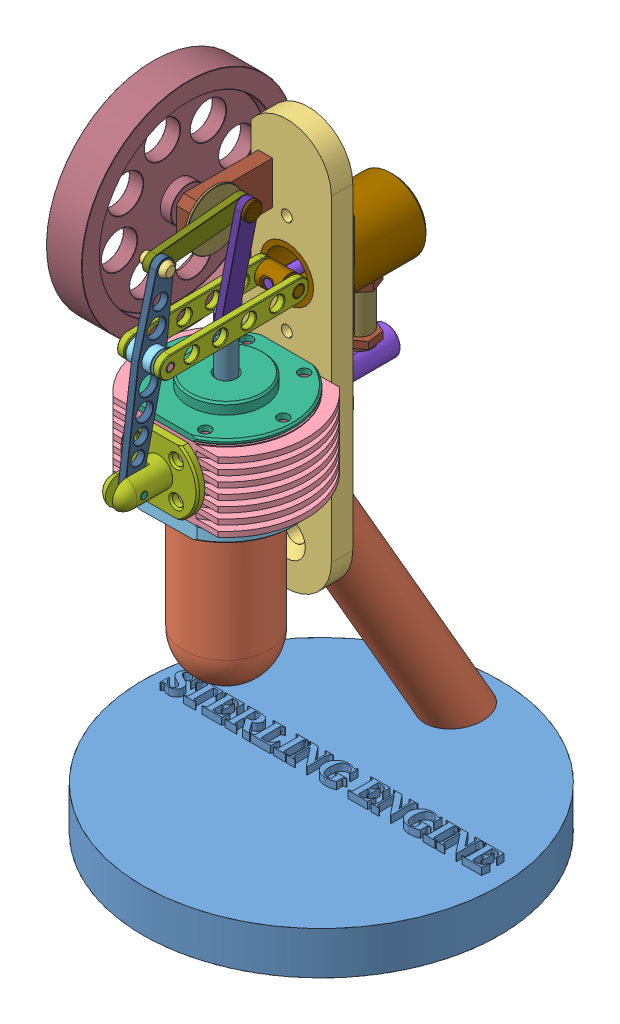
SolidWorks assembly Assem1, configuration Default. Lengths in mm.
Overall size (100 197.34 113.42).
33 component instances, 30 part files, 75 mates.
Components (placement in the parent):
- 19. Stand Base-1: 19. Stand Base [Default] at (62.9153 46.9775 56.3117) size (100 14 100)
- 20 Stand Shaft-1: 20 Stand Shaft [Default] at (62.9153 141.83 66.4864) x (0 0.5 -0.866025) z (-1 0 0) size (15 100 15)
- 30. Stand Base-1: 30. Stand Base [Default] at (62.9153 168.08 59.9912) x (0 -1 0) z (0 0 1) size (114 25 6)
- 31. Cylinder-1: 31. Cylinder [Default] at (62.9153 147.58 82.9912) x (0 0 -1) z (0 1 0) size (34 45 20)
- 17. Cylinder Cover-1: 17. Cylinder Cover [Default] at (62.6849 147.58 82.8607) x (-0.999863 0 0.016544) z (0.016544 0 0.999863) size (38 4 34)
- 18. Cylinder Head-1: 18. Cylinder Head [Default] at (62.9153 167.58 82.9912) size (38 9.5 34)
- 28. Stand Link Holder-1: 28. Stand Link Holder [Default] at (62.9153 157.58 99.9912) x (0 -1 0) z (-1 0 0) size (18 16.87 22)
- 29. Flowshaft-1: 29. Flowshaft [Default] at (62.9153 157.58 37.9912) x (0 0 1) z (-1 0 0) size (34 22 22)
- 27. Transfer Piston-1: 27. Transfer Piston [Default] at (62.9153 187.58 56.9912) x (0 -1 0) z (1 0 0) size (35 30 20)
- 26. Support Link-1: 26. Support Link [Default] at (62.9153 187.0997 104.6443) x (0 0.983989 -0.17823) z (-1 0 0) size (55 8 2)
- 1. Support Base-1: 1. Support Base [Default] at (54.9153 207.58 77.4912) size (4 12 23)
- 9. Eccentric Sheave-1: 9. Eccentric Sheave [Default] at (47.3153 207.58 82.9912) x (0 -0.965995 -0.258562) z (0 -0.258562 0.965995) size (16 12.6 16)
- 25. Flywheel-1: 25. Flywheel [Default] at (47.4153 207.58 82.9912) x (0 0.258562 -0.965995) z (1 0 0) size (60 60 10)
- 16. Piston Rod-1: 16. Piston Rod [Default] at (62.9153 150.8125 82.9912) x (0 1 0) z (1 0 0) size (36 5 5)
- 14. piston-1: 14. piston [Default] at (62.9153 151.4075 82.9912) x (-0.861018 0 -0.508575) z (0.508575 0 -0.861018) size (19.5 7 19.5)
- 4. Cranckrod -1-1: 4. Cranckrod -1 [Default] at (60.9153 207.9554 89.1375) x (0 0.097997 -0.995187) z (1 0 0) size (29 5 2)
- 5. Cranckrod -2-1: 5. Cranckrod -2 [Default] at (63.9153 196.972 80.0932) x (0 0.972754 -0.231839) z (-1 0 0) size (30 5 2)
- 6. Cranck Bolt 1-1: 6. Cranck Bolt 1 [Default] at (58.9153 209.1314 77.1952) x (0 -1 0) z (0 0 1) size (5 6 5)
- 12. Inner Heater-1: 12. Inner Heater [Default] at (62.9153 153.8125 82.9912) x (-0.126237 0 -0.992) z (-0.992 0 0.126237) size (19.5 41 19.5)
- 13. Outer Heater-1: 13. Outer Heater [Default] at (62.9153 110.58 82.9912) x (0.260894 0 -0.965367) z (-0.965367 0 -0.260894) size (24 47 24)
- 7. Cranckrod Bolt-2-1: 7. Cranckrod Bolt-2 [Default] at (57.9153 206.7795 101.0797) x (0 -0.807608 -0.58972) z (0 -0.58972 0.807608) size (4 7.5 4)
- 3. Connecting Link Stud-1: 3. Connecting Link Stud [Default] at (62.9153 187.0997 104.6443) x (0 0.000006 1) z (-1 0 0) size (2 2 12)
- 11. Bush-1: 11. Bush [Default] at (63.9153 187.0997 104.7548) x (0 -1 -0.000012) z (0 -0.000012 1) size (6 2.5 6)
- 11. Bush-2: 11. Bush [Default] at (59.4153 187.0729 104.7515) x (0 -0.970069 -0.242828) z (0 -0.242828 0.970069) size (6 2.5 6)
- 8. Support Link Stud-1: 8. Support Link Stud [Default] at (62.9153 157.58 109.9912) x (0 1 0) z (0 0 1) size (2 8 2)
- 2. Connecting Link-1: 2. Connecting Link [Default] at (66.9153 187.3399 86.6459) x (0 0.013343 -0.999911) z (1 0 0) size (42 6 2)
- 2. Connecting Link-2: 2. Connecting Link [Default] at (56.9153 187.3399 86.6459) x (0 0.013343 -0.999911) z (1 0 0) size (42 6 2)
- 21. Cylindrer Rod-1: 21. Cylindrer Rod [Default] at (62.9153 187.58 46.1475) x (0.999748 -0.022465 0) z (-0.022465 -0.999748 0) size (3 25 3)
- 24. Crosshead-1: 24. Crosshead [Default] at (56.9153 187.58 68.6475) x (0 0 1) z (0 1 0) size (6 12 6)
- 23. Piston-1: 23. Piston [Default] at (62.9153 187.58 54.6475) x (0.925615 -0.378466 0) z (0.378466 0.925615 0) size (12 12 12)
- 10. Connector-1: 10. Connector [Default] at (62.9153 175.58 45.4912) x (0 -1 0) z (-0.165629 0 0.986188) size (9 9.24 8)
- 10. Connector-2: 10. Connector [Default] at (62.9153 163.83 45.4912) x (0 1 0) z (-0.400731 0 0.916196) size (9 9.24 8)
- 22. tube-1: 22. tube [Default] at (62.9153 164.21 45.4912) x (0.999909 0 -0.013519) z (0.013519 0 0.999909) size (6.5 11 6.5)
Mates (geometry in assembly coordinates):
- Concentric1: concentric anti-aligned: cylinder of 19. Stand Base-1 through (62.9153 58.9775 21.3117) axis (0 1 0) radius 2.9; cylinder of 20 Stand Shaft-1 through (62.9153 68.9775 21.3117) axis (0 -1 0) radius 2.5
- Coincident1: coincident anti-aligned: plane of 19. Stand Base-1 through (62.9153 58.9775 56.3117) normal (0 1 0); plane of 20 Stand Shaft-1 through (112.9153 58.9775 9.9912) normal (0 -1 0)
- Coincident2: coincident anti-aligned: plane of 19. Stand Base-1 through (62.9153 46.9775 56.3117) normal (1 0 0); plane of 20 Stand Shaft-1 through (62.9153 141.83 66.4864) normal (-1 0 0)
- Concentric2: concentric aligned: circle of 20 Stand Shaft-1; circle of 30. Stand Base-1
- Coincident3: coincident anti-aligned: plane of 20 Stand Shaft-1 through (112.9153 145.58 59.9912) normal (0 0 1); plane of 30. Stand Base-1 through (62.9153 123.58 59.9912) normal (0 0 -1)
- Coincident4: coincident anti-aligned: plane of 20 Stand Shaft-1 through (62.9153 141.83 66.4864) normal (-1 0 0); plane of 30. Stand Base-1 through (62.9153 168.08 59.9912) normal (1 0 0)
- Concentric4: concentric aligned: cylinder of 30. Stand Base-1 through (62.9153 157.58 65.9912) axis (0 0 -1) radius 4; cylinder of 31. Cylinder-1 through (62.9153 157.58 99.9922) axis (0 0 -1) radius 4
- Concentric5: concentric aligned: cylinder of 30. Stand Base-1 through (67.865 162.5298 65.9912) axis (0 0 -1) radius 1.55; cylinder of 31. Cylinder-1 through (67.865 162.5298 69.9912) axis (0 0 -1) radius 1.5
- Coincident5: coincident anti-aligned: plane of 30. Stand Base-1 through (62.9153 123.58 65.9912) normal (0 0 1); plane of 31. Cylinder-1 through (77.6547 167.58 65.9912) normal (0 0 -1)
- Concentric19: concentric aligned: cylinder of 31. Cylinder-1 through (54.9153 161.58 96.8476) axis (0 1 0) radius 1.5; cylinder of 17. Cylinder Cover-1 through (54.9153 143.58 96.8476) axis (0 1 0) radius 1.55
- Coincident8: coincident anti-aligned: plane of 31. Cylinder-1 through (62.9153 147.58 82.9912) normal (0 -1 0); plane of 17. Cylinder Cover-1 through (62.6849 147.58 82.8607) normal (0 1 0)
- Concentric20: concentric anti-aligned: cylinder of 31. Cylinder-1 through (62.9153 167.58 82.9912) axis (0 -1 0) radius 10.5; cylinder of 18. Cylinder Head-1 through (62.9153 162.58 82.9912) axis (0 1 0) radius 2.5
- Concentric21: concentric anti-aligned: cylinder of 31. Cylinder-1 through (54.9153 161.58 96.8476) axis (0 1 0) radius 1.5; cylinder of 18. Cylinder Head-1 through (54.9153 169.08 96.8476) axis (0 -1 0) radius 1.55
- Coincident9: coincident anti-aligned: plane of 31. Cylinder-1 through (62.9153 167.58 82.9912) normal (0 1 0); plane of 18. Cylinder Head-1 through (62.9153 167.58 82.9912) normal (0 -1 0)
- Concentric24: concentric aligned: cylinder of 31. Cylinder-1 through (62.9153 157.58 99.9912) axis (0 0 1) radius 3; cylinder of 28. Stand Link Holder-1 through (62.9153 157.58 98.9912) axis (0 0 1) radius 3
- Concentric25: concentric aligned: cylinder of 31. Cylinder-1 through (67.865 162.5298 95.9912) axis (0 0 1) radius 1.5; cylinder of 28. Stand Link Holder-1 through (67.865 162.5298 99.9912) axis (0 0 1) radius 1.55
- Coincident10: coincident anti-aligned: plane of 31. Cylinder-1 through (77.6547 167.58 99.9912) normal (0 0 1); plane of 28. Stand Link Holder-1 through (62.9153 157.58 99.9912) normal (0 0 -1)
- Concentric26: concentric anti-aligned: cylinder of 30. Stand Base-1 through (62.9153 157.58 65.9912) axis (0 0 -1) radius 4; cylinder of 29. Flowshaft-1 through (62.9153 157.58 71.9912) axis (0 0 1) radius 4
- Concentric27: concentric aligned: cylinder of 30. Stand Base-1 through (67.865 162.5298 65.9912) axis (0 0 -1) radius 1.55; circle of 29. Flowshaft-1
- Coincident12: coincident anti-aligned: plane of 30. Stand Base-1 through (62.9153 123.58 59.9912) normal (0 0 -1); plane of 29. Flowshaft-1 through (62.9153 168.58 59.9912) normal (0 0 1)
- Concentric30: concentric anti-aligned: cylinder of 28. Stand Link Holder-1 through (77.4153 157.58 109.9912) axis (-1 0 0) radius 1; cylinder of 26. Support Link-1 through (61.9153 157.58 109.9912) axis (1 0 0) radius 1
- Coincident15: coincident anti-aligned: plane of 28. Stand Link Holder-1 through (63.9153 172.08 105.4912) normal (-1 0 0); plane of 26. Support Link-1 through (63.9153 157.58 109.9912) normal (1 0 0)
- Concentric31: concentric anti-aligned: cylinder of 30. Stand Base-1 through (56.9153 211.58 62.9912) axis (0 0 1) radius 1.55; cylinder of 1. Support Base-1 through (56.9153 211.58 75.9912) axis (0 0 -1) radius 1.5
- Concentric32: concentric anti-aligned: cylinder of 30. Stand Base-1 through (56.9153 203.58 62.9912) axis (0 0 1) radius 1.55; cylinder of 1. Support Base-1 through (56.9153 203.58 75.9912) axis (0 0 -1) radius 1.5
- Coincident16: coincident anti-aligned: plane of 30. Stand Base-1 through (62.9153 123.58 65.9912) normal (0 0 1); plane of 1. Support Base-1 through (58.9153 213.58 65.9912) normal (0 0 -1)
- Concentric33: concentric anti-aligned: cylinder of 1. Support Base-1 through (54.9153 207.58 82.9912) axis (1 0 0) radius 2; cylinder of 9. Eccentric Sheave-1 through (58.9153 207.58 82.9912) axis (-1 0 0) radius 2
- Coincident17: coincident anti-aligned: plane of 1. Support Base-1 through (58.9153 207.58 77.4912) normal (1 0 0); plane of 9. Eccentric Sheave-1 through (58.9153 207.58 82.9912) normal (-1 0 0)
- Concentric34: concentric aligned: cylinder of 9. Eccentric Sheave-1 through (58.9153 207.58 82.9912) axis (-1 0 0) radius 2; cylinder of 25. Flywheel-1 through (42.4153 207.58 82.9912) axis (-1 0 0) radius 2
- Distance2: distance = 2.5 mm anti-aligned: plane of 25. Flywheel-1 through (52.4153 207.58 82.9912) normal (1 0 0); plane of 1. Support Base-1 through (54.9153 207.58 77.4912) normal (-1 0 0)
- Coincident21: coincident anti-aligned: plane of 9. Eccentric Sheave-1 through (47.3153 207.58 82.9912) normal (0 -0.965995 -0.258562); plane of 25. Flywheel-1 through (47.4153 207.58 82.9912) normal (0 0.965995 0.258562)
- Concentric35: concentric anti-aligned: cylinder of 18. Cylinder Head-1 through (62.9153 162.58 82.9912) axis (0 1 0) radius 2.5; cylinder of 16. Piston Rod-1 through (62.9153 150.8125 82.9912) axis (0 -1 0) radius 2.5
- Concentric37: concentric aligned: cylinder of 9. Eccentric Sheave-1 through (67.7153 209.1314 77.1952) axis (-1 0 0) radius 1.5; cylinder of 4. Cranckrod -1-1 through (61.9153 209.1314 77.1952) axis (-1 0 0) radius 1.55
- Concentric38: concentric anti-aligned: cylinder of 26. Support Link-1 through (61.9153 206.7795 101.0797) axis (1 0 0) radius 1.5; cylinder of 4. Cranckrod -1-1 through (61.9153 206.7795 101.0797) axis (-1 0 0) radius 1.55
- Coincident23: coincident anti-aligned: plane of 9. Eccentric Sheave-1 through (59.9153 207.58 82.9912) normal (1 0 0); plane of 4. Cranckrod -1-1 through (59.9153 206.7795 101.0797) normal (-1 0 0)
- Concentric39: concentric anti-aligned: cylinder of 4. Cranckrod -1-1 through (61.9153 209.1314 77.1952) axis (-1 0 0) radius 1.55; cylinder of 5. Cranckrod -2-1 through (61.9153 209.1314 77.1952) axis (1 0 0) radius 1.55
- Coincident24: coincident anti-aligned: plane of 4. Cranckrod -1-1 through (61.9153 206.7795 101.0797) normal (1 0 0); plane of 5. Cranckrod -2-1 through (61.9153 184.8125 82.9912) normal (-1 0 0)
- Concentric40: concentric aligned: cylinder of 16. Piston Rod-1 through (57.9153 184.8125 82.9912) axis (1 0 0) radius 1.25; cylinder of 5. Cranckrod -2-1 through (61.9153 184.8125 82.9912) axis (1 0 0) radius 1.55
- Concentric41: concentric anti-aligned: cylinder of 5. Cranckrod -2-1 through (61.9153 209.1314 77.1952) axis (1 0 0) radius 1.55; cylinder of 6. Cranck Bolt 1-1 through (58.9153 209.1314 77.1952) axis (-1 0 0) radius 1.5
- Coincident25: coincident anti-aligned: plane of 5. Cranckrod -2-1 through (63.9153 184.8125 82.9912) normal (1 0 0); plane of 6. Cranck Bolt 1-1 through (63.9153 206.6314 77.1952) normal (-1 0 0)
- Concentric42: concentric aligned: cylinder of 16. Piston Rod-1 through (62.9153 150.8125 82.9912) axis (0 -1 0) radius 2.5; cylinder of 14. piston-1 through (62.9153 151.4075 82.9912) axis (0 -1 0) radius 9.75
- Coincident26: coincident aligned: plane of 16. Piston Rod-1 through (62.9153 150.8125 82.9912) normal (0 -1 0); plane of 14. piston-1 through (57.7492 150.8125 79.9398) normal (0 -1 0)
- Concentric43: concentric aligned: cylinder of 16. Piston Rod-1 through (62.9153 150.8125 82.9912) axis (0 -1 0) radius 2.5; cylinder of 12. Inner Heater-1 through (62.9153 112.8125 82.9912) axis (0 -1 0) radius 9.25
- Coincident27: coincident anti-aligned: plane of 14. piston-1 through (54.5203 153.8125 78.0326) normal (0 -1 0); plane of 12. Inner Heater-1 through (62.9153 153.8125 82.9912) normal (0 1 0)
- Concentric44: concentric aligned: cylinder of 16. Piston Rod-1 through (62.9153 150.8125 82.9912) axis (0 -1 0) radius 2.5; cylinder of 13. Outer Heater-1 through (62.9153 100.08 82.9912) axis (0 -1 0) radius 12
- Coincident28: coincident anti-aligned: plane of 17. Cylinder Cover-1 through (62.6849 145.58 82.8607) normal (0 -1 0); plane of 13. Outer Heater-1 through (65.6547 145.58 72.8548) normal (0 1 0)
- Concentric45: concentric aligned: cylinder of 26. Support Link-1 through (61.9153 206.7795 101.0797) axis (1 0 0) radius 1.5; cylinder of 7. Cranckrod Bolt-2-1 through (65.4153 206.7795 101.0797) axis (1 0 0) radius 1.5
- Coincident29: coincident anti-aligned: plane of 26. Support Link-1 through (63.9153 157.58 109.9912) normal (1 0 0); plane of 7. Cranckrod Bolt-2-1 through (63.9153 206.7795 101.0797) normal (-1 0 0)
- Concentric46: concentric anti-aligned: circle of 26. Support Link-1; cylinder of 3. Connecting Link Stud-1 through (56.9153 187.0997 104.6443) axis (1 0 0) radius 1
- Coincident31: coincident aligned: plane of 26. Support Link-1 through (62.9153 187.0997 104.6443) normal (-1 0 0); plane of 3. Connecting Link Stud-1 through (62.9153 187.0997 104.6443) normal (-1 0 0)
- Concentric47: concentric anti-aligned: cylinder of 3. Connecting Link Stud-1 through (56.9153 187.0997 104.6443) axis (1 0 0) radius 1; cylinder of 11. Bush-1 through (66.4153 187.0997 104.6443) axis (-1 0 0) radius 1
- Coincident32: coincident anti-aligned: plane of 26. Support Link-1 through (63.9153 157.58 109.9912) normal (1 0 0); plane of 11. Bush-1 through (63.9153 187.0997 104.7548) normal (-1 0 0)
- Concentric48: concentric anti-aligned: cylinder of 3. Connecting Link Stud-1 through (56.9153 187.0997 104.6443) axis (1 0 0) radius 1; cylinder of 11. Bush-2 through (61.9153 187.0997 104.6443) axis (-1 0 0) radius 1
- Coincident33: coincident anti-aligned: plane of 26. Support Link-1 through (61.9153 157.58 109.9912) normal (-1 0 0); plane of 11. Bush-2 through (61.9153 187.0729 104.7515) normal (1 0 0)
- Concentric49: concentric anti-aligned: cylinder of 28. Stand Link Holder-1 through (77.4153 157.58 109.9912) axis (-1 0 0) radius 1; cylinder of 8. Support Link Stud-1 through (58.9153 157.58 109.9912) axis (1 0 0) radius 1
- Tangent2: tangent aligned: cylinder of 28. Stand Link Holder-1 through (62.9153 157.58 101.9912) axis (0 0 -1) radius 4; plane of 8. Support Link Stud-1 through (66.9153 157.58 109.9912) normal (1 0 0)
- Concentric50: concentric anti-aligned: cylinder of 3. Connecting Link Stud-1 through (56.9153 187.0997 104.6443) axis (1 0 0) radius 1; cylinder of 2. Connecting Link-1 through (68.9153 187.0997 104.6443) axis (-1 0 0) radius 1
- Coincident34: coincident aligned: plane of 3. Connecting Link Stud-1 through (68.9153 187.0997 104.6443) normal (1 0 0); plane of 2. Connecting Link-1 through (68.9153 187.58 68.6475) normal (1 0 0)
- Concentric51: concentric anti-aligned: cylinder of 3. Connecting Link Stud-1 through (56.9153 187.0997 104.6443) axis (1 0 0) radius 1; cylinder of 2. Connecting Link-2 through (58.9153 187.0997 104.6443) axis (-1 0 0) radius 1
- Coincident35: coincident aligned: plane of 3. Connecting Link Stud-1 through (56.9153 187.0997 104.6443) normal (-1 0 0); plane of 2. Connecting Link-2 through (56.9153 187.58 68.6475) normal (-1 0 0)
- Concentric53: concentric anti-aligned: cylinder of 21. Cylindrer Rod-1 through (62.9153 187.58 71.1475) axis (0 0 -1) radius 1.5; cylinder of 24. Crosshead-1 through (62.9153 187.58 65.6475) axis (0 0 1) radius 1.5
- Coincident36: coincident aligned: plane of 21. Cylindrer Rod-1 through (62.9153 187.58 71.1475) normal (0 0 1); plane of 24. Crosshead-1 through (62.9153 187.58 71.1475) normal (0 0 1)
- Concentric54: concentric aligned: cylinder of 2. Connecting Link-1 through (68.9153 187.58 68.6475) axis (-1 0 0) radius 1.5; cylinder of 24. Crosshead-1 through (56.9153 187.58 68.6475) axis (-1 0 0) radius 1.5
- Concentric55: concentric aligned: cylinder of 2. Connecting Link-2 through (58.9153 187.58 68.6475) axis (-1 0 0) radius 1.5; cylinder of 24. Crosshead-1 through (56.9153 187.58 68.6475) axis (-1 0 0) radius 1.5
- Concentric56: concentric anti-aligned: cylinder of 21. Cylindrer Rod-1 through (62.9153 187.58 71.1475) axis (0 0 -1) radius 1.5; cylinder of 23. Piston-1 through (62.9153 187.58 42.6475) axis (0 0 1) radius 6
- Coincident37: coincident anti-aligned: plane of 21. Cylindrer Rod-1 through (62.9153 187.58 46.1475) normal (0 0 -1); plane of 23. Piston-1 through (62.9153 187.58 46.1475) normal (0 0 1)
- Concentric57: concentric aligned: cylinder of 30. Stand Base-1 through (62.9153 201.58 65.9912) axis (0 0 -1) radius 1.55; cylinder of 27. Transfer Piston-1 through (62.9153 201.58 59.9912) axis (0 0 -1) radius 1.55
- Concentric58: concentric anti-aligned: cylinder of 30. Stand Base-1 through (62.9153 187.58 65.9912) axis (0 0 -1) radius 7.5; cylinder of 27. Transfer Piston-1 through (62.9153 187.58 40.9912) axis (0 0 1) radius 6
- Coincident38: coincident anti-aligned: plane of 30. Stand Base-1 through (62.9153 123.58 59.9912) normal (0 0 -1); plane of 27. Transfer Piston-1 through (62.9153 187.58 59.9912) normal (0 0 1)
- Concentric59: concentric anti-aligned: cylinder of 27. Transfer Piston-1 through (62.9153 187.58 40.9912) axis (0 0 1) radius 6; cylinder of 21. Cylindrer Rod-1 through (62.9153 187.58 71.1475) axis (0 0 -1) radius 1.5
- Concentric60: concentric aligned: cylinder of 27. Transfer Piston-1 through (62.9153 184.58 45.4912) axis (0 -1 0) radius 2.5; cylinder of 10. Connector-1 through (62.9153 180.58 45.4912) axis (0 -1 0) radius 2.5
- Coincident39: coincident anti-aligned: plane of 27. Transfer Piston-1 through (62.9153 178.58 45.4912) normal (0 -1 0); plane of 10. Connector-1 through (62.9153 178.58 45.4912) normal (0 1 0)
- Concentric61: concentric aligned: cylinder of 29. Flowshaft-1 through (62.9153 158.83 45.4912) axis (0 1 0) radius 2.5; cylinder of 10. Connector-2 through (62.9153 158.83 45.4912) axis (0 1 0) radius 2.5
- Coincident40: coincident anti-aligned: plane of 29. Flowshaft-1 through (62.9153 160.83 37.9912) normal (0 1 0); plane of 10. Connector-2 through (62.9153 160.83 45.4912) normal (0 -1 0)
- Concentric62: concentric anti-aligned: cylinder of 10. Connector-1 through (62.9153 171.58 45.4912) axis (0 1 0) radius 2.75; cylinder of 22. tube-1 through (62.9153 175.21 45.4912) axis (0 -1 0) radius 2.75
- Distance3: distance = 0.38 mm anti-aligned: plane of 22. tube-1 through (62.9153 164.21 45.4912) normal (0 -1 0); plane of 10. Connector-2 through (62.9153 163.83 45.4912) normal (0 1 0)
